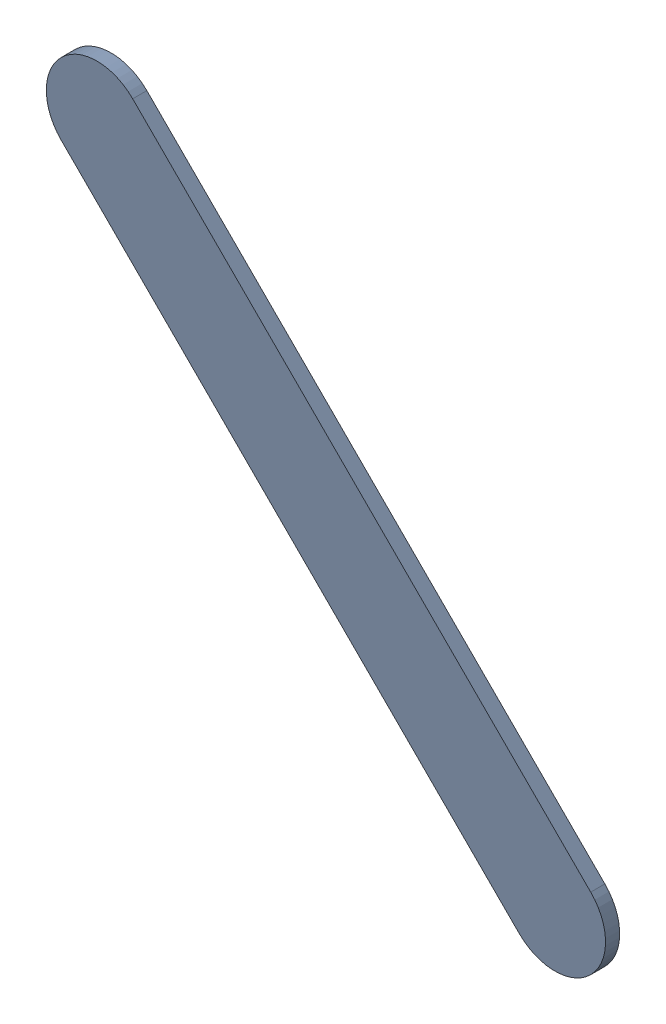
SolidWorks assembly Track (29.9mm,52.7mm)(31.05mm,51.55mm) on Top Layer, configuration Predeterminado. Lengths in mm.
Overall size (1.4 1.4 0.04).
2 component instances, 1 part files, 0 mates.
Components (placement in the parent):
- Track (29.9mm,52.7mm)(31.05mm,51.55mm) on Top Layer-1-1: Track (29.9mm,52.7mm)(31.05mm,51.55mm) on Top Layer-1 [Predeterminado] at (-68.317 -44.187 -0.0457) size (1.4 1.4 0.04)
  - Track (29.9mm,52.7mm)(31.05mm,51.55mm) on Top Layer-Part-1-1: Track (29.9mm,52.7mm)(31.05mm,51.55mm) on Top Layer-Part-1 [Predeterminado] at origin size (1.4 1.4 0.04)
